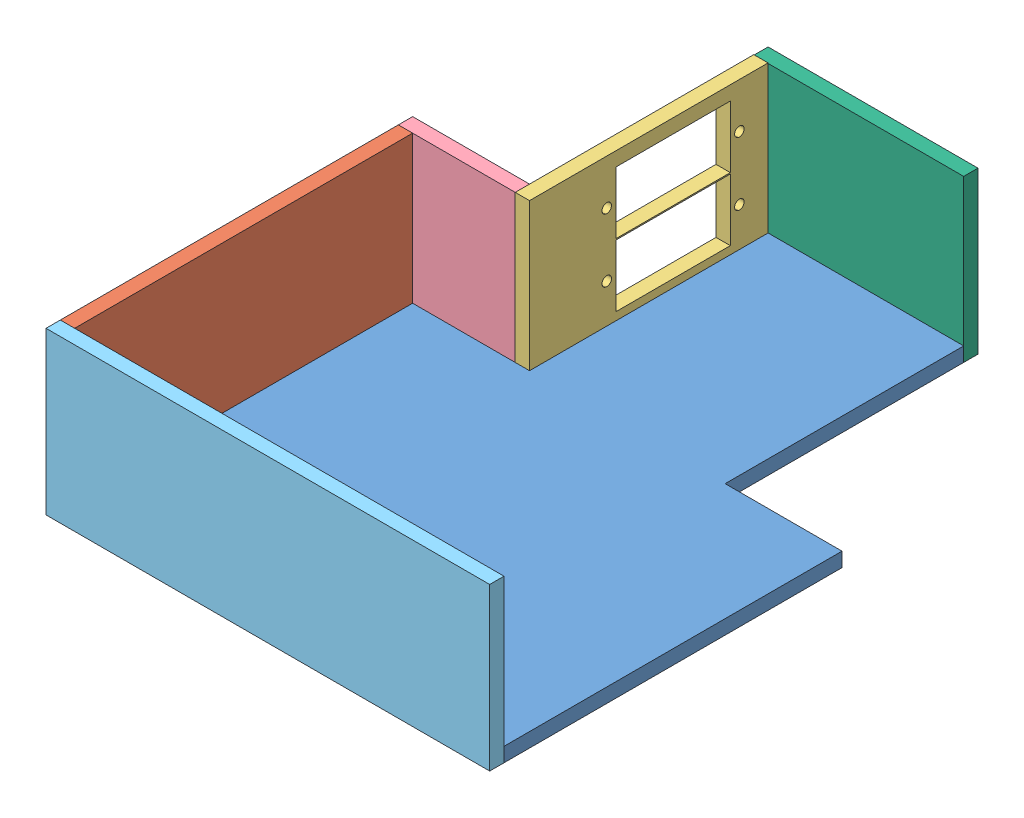
SolidWorks assembly assembly of new enclosure round 5, configuration Default. Lengths in mm.
Overall size (93 56.71 126.85).
6 component instances, 6 part files, 12 mates.
Components (placement in the parent):
- base of new enclosure-1: base of new enclosure [Default] at (-16.1284 18.8437 -6.4312) size (90 3 120.85)
- side1 of new enclosure-1: side1 of new enclosure [Default] at (-64.1284 61.2371 -10.8923) size (3 33.88 70.85)
- side2 of new enclosure-1: side2 of new enclosure [Default] at (-39.6284 75.5574 -26.1974) size (3 33.88 50)
- side3 of new enclosure-1: side3 of new enclosure [Default] at (-80.6668 -3.993 -17.2358) x (0 0 -1) z (-1 0 0) size (3 33.88 24.5)
- side4 of new enclosure-1: side4 of new enclosure [Default] at (-23.09 75.5574 56.6148) x (0 0 -1) z (1 0 0) size (3 56.71 93)
- side5 of new enclosure-1: side5 of new enclosure [Default] at (1.41 75.5574 -67.2358) x (0 0 -1) z (1 0 0) size (3 56.71 44)
Mates (geometry in assembly coordinates):
- Coincident4: coincident: plane of base of new enclosure-1 through (-36.6284 21.8437 -67.2358) normal (-1 0 0); plane of side2 of new enclosure-1 through (-36.6284 75.5574 -26.1974) normal (1 0 0)
- Coincident5: coincident: plane of base of new enclosure-1 through (-36.6284 21.8437 -67.2358) normal (-1 0 0); plane of side2 of new enclosure-1 through (-36.6284 75.5574 -26.1974) normal (1 0 0)
- Coincident6: coincident: plane of base of new enclosure-1 through (-36.6284 21.8437 -17.2358) normal (0 0 -1); plane of side3 of new enclosure-1 through (-80.6668 -3.993 -17.2358) normal (0 0 1)
- Coincident7: coincident: plane of side2 of new enclosure-1 through (-39.6284 75.5574 -26.1974) normal (-1 0 0); plane of side3 of new enclosure-1 through (-39.6284 52.7207 -20.2358) normal (1 0 0)
- Coincident9: coincident: line of base of new enclosure-1 through (-36.6284 18.8437 -17.2358) axis (-1 0 0); line of side3 of new enclosure-1 through (-39.6284 18.8437 -17.2358) axis (-1 0 0)
- Coincident10: coincident: plane of base of new enclosure-1 through (-61.1284 21.8437 -17.2358) normal (-1 0 0); plane of side1 of new enclosure-1 through (-61.1284 61.2371 -10.8923) normal (1 0 0)
- Coincident11: coincident: plane of base of new enclosure-1 through (-61.1284 21.8437 53.6148) normal (0 0 1); plane of side4 of new enclosure-1 through (-23.09 75.5574 53.6148) normal (0 0 -1)
- Coincident12: coincident: line of side1 of new enclosure-1 through (-64.1284 52.7207 53.6148) axis (0 -1 0); line of side4 of new enclosure-1 through (-64.1284 18.8437 53.6148) axis (0 1 0)
- Coincident13: coincident: line of base of new enclosure-1 through (-61.1284 18.8437 53.6148) axis (1 0 0); line of side4 of new enclosure-1 through (28.8716 18.8437 53.6148) axis (-1 0 0)
- Coincident14: coincident: plane of base of new enclosure-1 through (4.3716 21.8437 -67.2358) normal (0 0 -1); plane of side5 of new enclosure-1 through (1.41 75.5574 -67.2358) normal (0 0 1)
- Coincident15: coincident: line of side2 of new enclosure-1 through (-39.6284 18.8437 -67.2358) axis (0 1 0); line of side5 of new enclosure-1 through (-39.6284 18.8437 -67.2358) axis (0 1 0)
- Coincident16: coincident: plane of base of new enclosure-1 through (-16.1284 18.8437 -6.4312) normal (0 -1 0); plane of side5 of new enclosure-1 through (4.3716 18.8437 -70.2358) normal (0 -1 0)
